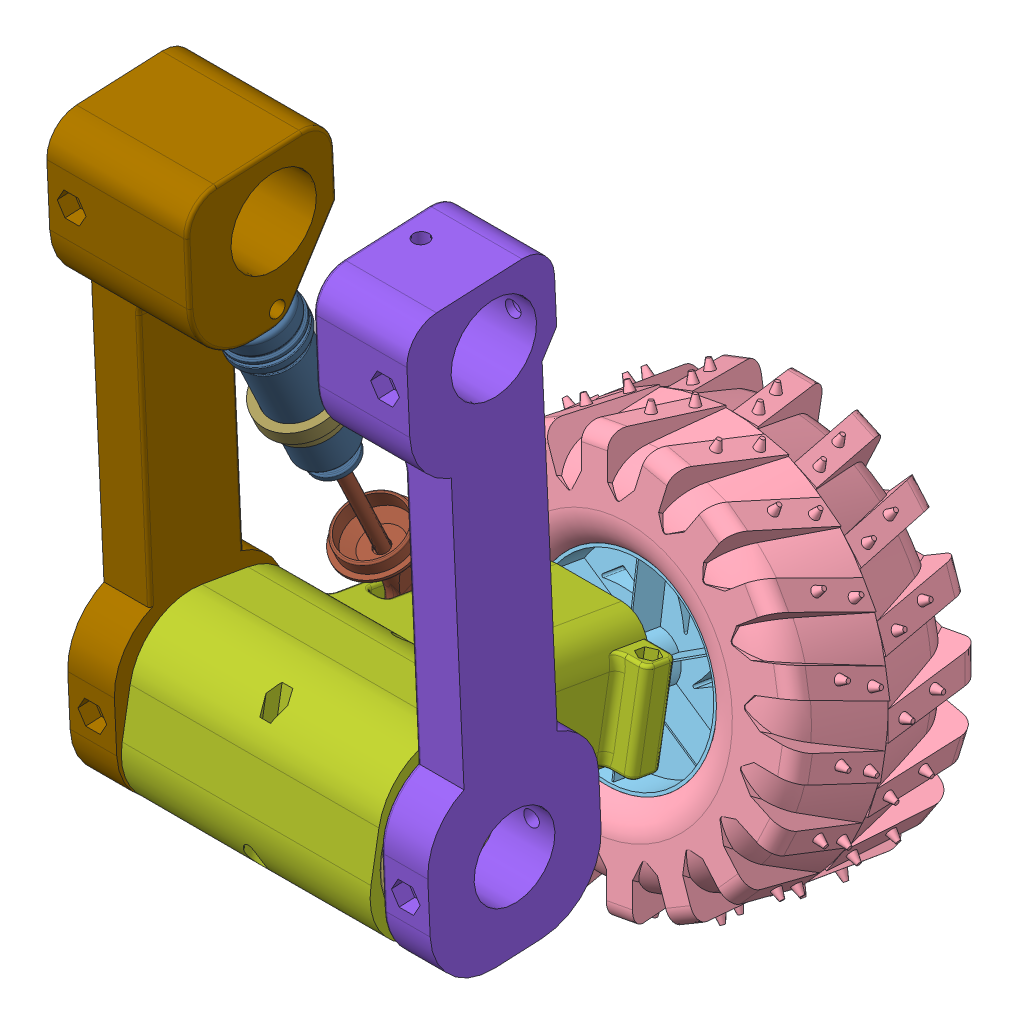
SolidWorks assembly ArmLeft, configuration Default. Lengths in mm.
Overall size (177.35 286.09 198.05).
17 component instances, 13 part files, 21 mates.
Components (placement in the parent):
- Pololu_GearMotor_37Dmm-1: Pololu_GearMotor_37Dmm [Default] at (-21.9768 -12.8642 -3.5291) x (0.802348 -0.588163 0.101494) z (-0.000058 0.16997 0.985449) size (51.49 51.49 82.3)
  - Pololu_ShaftGearMotor6mm-1: Pololu_ShaftGearMotor6mm [Default] at (9.8861 24.7007 16.6991) x (0.930815 0.36549 0) z (0 0 1) size (6 6 22)
  - Pololu_GearMotor_37Dmm-1: Pololu_GearMotor_37Dmm [Default] at (5.7082 30.3171 38.6991) x (-0.802354 -0.596848 0) z (0 0 -1) size (36.8 36.8 66.8)
- BallBearing16412RS-1: BallBearing16412RS [Default] at (40.4875 7.4102 -38.9392) x (-0.000059 0.14438 0.989522) z (-1 0 -0.000059) size (50.8 50.8 14.29)
- BallBearing16412RS-2: BallBearing16412RS [Default] at (-24.8068 -116.646 75.0398) x (-0.000012 0.977505 0.210913) z (-1 0 -0.000059) size (50.8 50.8 14.29)
- Wheel-1: Wheel [Default] at (10.2673 7.5209 -36.2694) x (0.772441 0.625854 -0.107901) z (0.000058 -0.16997 -0.985449) size (126 126 62.61)
  - Tire-1: Tire [Varsayılan] at origin size (126 126 62.61)
  - tire_rim-1: tire_rim [Varsayılan] at (-6.6946 4.5427 -50) size (60 60 50)
- HexWheelAdapter12_6mm-1: HexWheelAdapter12_6mm [Default] at (0.6974 2.585 4.1572) x (0.915588 -0.396258 0.068401) z (-0.000058 0.16997 0.985449) size (13.44 15.09 20)
- MotorHolder1-1: MotorHolder1 [Default] at (-39.2994 67.3968 -49.5201) x (-0.000058 0.16997 0.985449) z (-1 0 -0.000059) size (107 55 80)
- SuspensionLeft^ArmLeft-2: SuspensionLeft^ArmLeft [Default] at (43.4554 -44.446 502.7733) x (0.000059 0.045994 -0.998942) z (1 0 0.000059) size (55 192.5 30) (virtual)
- Suspension-1: Suspension [Default] at (-42.3282 32.1448 437.3049) x (-0.000059 -0.045994 0.998942) z (-1 0 -0.000059) size (55 192.5 45)
- ShockAbsorber-2: ShockAbsorber [Default] at (55.2666 -147.4734 170.275) x (-0.43877 -0.880391 -0.179981) z (0.8986 -0.429892 -0.087818) size (131.97 54.45 80.5) (flexible)
  - ShockBody^ShockAbsorber-2: ShockBody^ShockAbsorber [Default] at (-175.6625 126.2845 -172.6656) x (-0.21547 0.970826 -0.105213) z (-0.43878 0 0.898594) size (22.02 74.55 22) (virtual)
  - Part4^ShockAbsorber-1: Part4^ShockAbsorber [Default] at (-171.5861 126.9478 -170.6751) x (0.21547 -0.970826 0.105213) z (0.43878 0 -0.898594) size (24 84.5 24) (virtual)
  - SpringAdjuster^ShockAbsorber-1: SpringAdjuster^ShockAbsorber [Default] at (-158.9409 130.6229 -164.5005) x (0.453017 -0.069167 -0.888815) z (-0.183661 0.968359 -0.168967) size (24.5 8.5 24.5) (virtual)
  - Spring^ShockAbsorber-2: Spring^ShockAbsorber [Default] at (-75.3079 244.2893 -165.8313) x (-0.870144 -0.24964 -0.424888) z (0.492715 -0.424888 -0.759409) (virtual)
Mates (geometry in assembly coordinates):
- Concentric29: concentric aligned: circle of HexWheelAdapter12_6mm-1; circle of Pololu_GearMotor_37Dmm-1/Pololu_ShaftGearMotor6mm-1
- Coincident27: coincident anti-aligned: plane of HexWheelAdapter12_6mm-1 through (0.697 3.6898 10.5626) normal (-0.000058 0.16997 0.985449); plane of Pololu_GearMotor_37Dmm-1/Pololu_ShaftGearMotor6mm-1 through (0.697 3.6898 10.5626) normal (0.000058 -0.16997 -0.985449)
- Concentric34: concentric anti-aligned: circle of Wheel-1/tire_rim-1; circle of HexWheelAdapter12_6mm-1
- Coincident36: coincident anti-aligned: plane of Wheel-1/tire_rim-1 through (0.6974 2.585 4.1572) normal (-0.000058 0.16997 0.985449); plane of HexWheelAdapter12_6mm-1 through (0.6974 2.585 4.1572) normal (0.000058 -0.16997 -0.985449)
- Parallel6: parallel anti-aligned: plane of Wheel-1/tire_rim-1 through (-2.0323 -1.3664 14.9863) normal (-0.079329 0.982343 -0.169439); plane of HexWheelAdapter12_6mm-1 through (-2.281 -0.1805 24.9293) normal (0.079329 -0.982343 0.169439)
- Concentric36: concentric anti-aligned: cylinder of BallBearing16412RS-2 through (-39.0962 27.5 107.4227) axis (1 0 0.000059) radius 25.4; cylinder of MotorHolder1-1 through (-24.8087 27.5 107.4235) axis (-1 0 -0.000059) radius 25.425
- Coincident37: coincident anti-aligned: plane of BallBearing16412RS-2 through (-24.8068 -116.646 75.0398) normal (1 0 0.000059); plane of MotorHolder1-1 through (-24.7994 67.3968 -49.5192) normal (-1 0 -0.000059)
- Concentric37: concentric aligned: cylinder of BallBearing16412RS-1 through (26.1913 27.5 107.4265) axis (1 0 0.000059) radius 25.4; cylinder of MotorHolder1-1 through (26.1913 27.5 107.4265) axis (1 0 0.000059) radius 25.425
- Coincident38: coincident anti-aligned: plane of BallBearing16412RS-1 through (26.2 7.4102 -38.94) normal (-1 0 -0.000059); plane of MotorHolder1-1 through (26.1913 27.5 107.4265) normal (1 0 0.000059)
- Concentric38: concentric anti-aligned: cylinder of Pololu_GearMotor_37Dmm-1/Pololu_GearMotor_37Dmm-1 through (0.6944 18.4066 54.7035) axis (0.000058 -0.16997 -0.985449) radius 18.4; cylinder of MotorHolder1-1 through (0.6958 14.3273 31.0527) axis (-0.000058 0.16997 0.985449) radius 18.45
- Concentric39: concentric anti-aligned: cylinder of Pololu_GearMotor_37Dmm-1/Pololu_GearMotor_37Dmm-1 through (0.6961 6.3244 25.8371) axis (-0.000058 0.16997 0.985449) radius 6; cylinder of MotorHolder1-1 through (0.6955 8.279 37.1698) axis (0.000058 -0.16997 -0.985449) radius 6
- Coincident40: coincident anti-aligned: plane of Pololu_GearMotor_37Dmm-1/Pololu_GearMotor_37Dmm-1 through (0.6958 14.3273 31.0527) normal (0.000058 -0.16997 -0.985449); plane of MotorHolder1-1 through (-39.3035 79.3589 19.8337) normal (-0.000058 0.16997 0.985449)
- Coincident19: coincident anti-aligned: plane of BallBearing16412RS-1 through (40.4875 7.4102 -38.9392) normal (1 0 0.000059); plane of SuspensionLeft^ArmLeft-2 through (40.4788 27.5 107.4274) normal (-1 0 -0.000059)
- Concentric62: concentric anti-aligned: cylinder of SuspensionLeft^ArmLeft-2 through (58.4784 172.3466 114.0975) axis (-1 0 -0.000059) radius 13.75; cylinder of Suspension-1 through (-57.3091 172.3466 114.0907) axis (1 0 0.000059) radius 13.75
- Concentric63: concentric aligned: cylinder of BallBearing16412RS-2 through (-39.0962 27.5 107.4227) axis (1 0 0.000059) radius 12.7; cylinder of Suspension-1 through (-57.3087 27.5 107.4216) axis (1 0 0.000059) radius 13
- Concentric64: concentric anti-aligned: cylinder of SuspensionLeft^ArmLeft-2 through (58.4784 172.3466 114.0975) axis (-1 0 -0.000059) radius 13.75; cylinder of Suspension-1 through (-57.3091 172.3466 114.0907) axis (1 0 0.000059) radius 13.75
- Concentric65: concentric anti-aligned: cylinder of SuspensionLeft^ArmLeft-2 through (58.4788 27.5 107.4285) axis (-1 0 -0.000059) radius 13; cylinder of Suspension-1 through (-57.3087 27.5 107.4216) axis (1 0 0.000059) radius 13
- Coincident42: coincident anti-aligned: plane of MotorHolder1-1 through (-39.2994 67.3968 -49.5201) normal (-1 0 -0.000059); plane of Suspension-1 through (-39.3087 27.5 107.4227) normal (1 0 0.000059)
- Distance20: distance = 1.5 mm anti-aligned: plane of Suspension-1 through (-17.8096 153.9057 123.2545) normal (-1 0 -0.000059); plane of ShockAbsorber-2/ShockBody^ShockAbsorber-2 through (-19.3079 106.6959 93.3282) normal (1 0 0.000059)
- Concentric67: concentric aligned: cylinder of Suspension-1 through (-12.309 147.373 112.9435) axis (-1 0 -0.000059) radius 2.5; cylinder of ShockAbsorber-2/ShockBody^ShockAbsorber-2 through (-19.309 147.373 112.9431) axis (-1 0 -0.000059) radius 2.5
- Concentric68: concentric aligned: cylinder of MotorHolder1-1 through (-8.7559 36.5547 60.1983) axis (-1 0 -0.000059) radius 1.75; cylinder of ShockAbsorber-2/Part4^ShockAbsorber-1 through (-20.6059 36.5547 60.1976) axis (-1 0 -0.000059) radius 1.5
